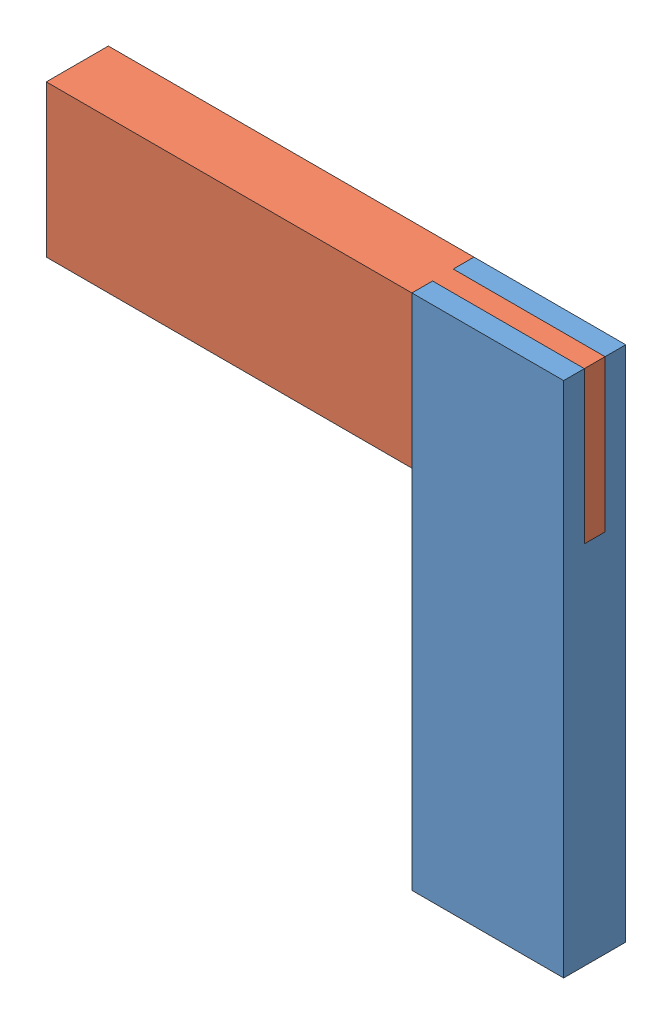
SolidWorks assembly Corner Bridle, configuration Default. Lengths in mm.
Overall size (150 150 18).
2 component instances, 2 part files, 3 mates.
Components (placement in the parent):
- Vertical piece-1: Vertical piece [Default] at (-127.0591 -78.679 58.1285) size (44 150 18)
- Top piece-1: Top piece [Default] at (-233.0591 27.321 58.1285) size (150 44 18)
Mates (geometry in assembly coordinates):
- Coincident1: coincident aligned: plane of Vertical piece-1 through (-127.0591 71.321 76.1285) normal (0 1 0); plane of Top piece-1 through (-233.0591 71.321 76.1285) normal (0 1 0)
- Coincident2: coincident anti-aligned: plane of Vertical piece-1 through (-127.0591 -78.679 76.1285) normal (-1 0 0); plane of Top piece-1 through (-127.0591 27.32 76.1285) normal (1 0 0)
- Coincident3: coincident anti-aligned: plane of Vertical piece-1 through (-127.0601 71.321 64.1285) normal (0 0 1); plane of Top piece-1 through (-83.0591 27.32 64.1285) normal (0 0 -1)
